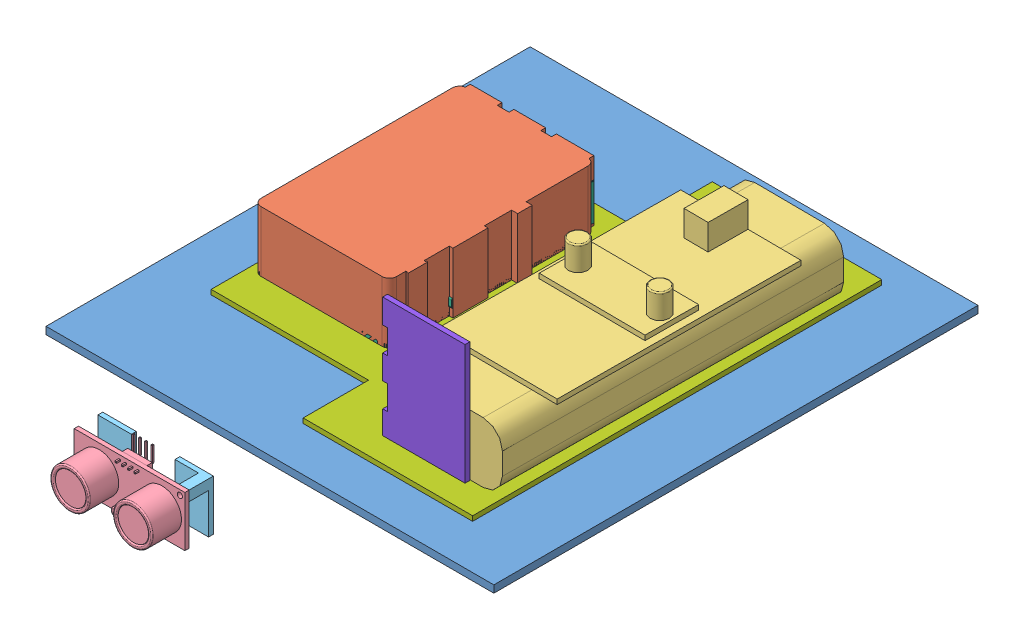
SolidWorks assembly BaugruppeRover, configuration Default. Lengths in mm.
Overall size (185 54.6 278.14).
10 component instances, 9 part files, 6 mates.
Components (placement in the parent):
- Grundplatte Security Rover-1: Grundplatte Security Rover [Default] at (60.9616 101.6265 161.5882) size (185 3 200)
- RaspberrySiluette-1: RaspberrySiluette [Standard] at (50.0622 106.6265 201.3551) x (0.000094 0 -1) z (0 1 0) size (87 58.5 25)
- AkkuSiluette-1: AkkuSiluette [Default] at (104.41 106.6265 160.86) x (0.999975 0 0.007086) z (-0.007086 0 0.999975) size (50 39 140)
- Teil3-1: Teil3 [Standard] at origin
- Baugruppe2-1: Baugruppe2 [Standard] at (48.9446 134.4073 330.5487) x (0 1 0) z (0 0 1) size (25.58 45.72 23.97)
  - hc sr04 ultrasonic sensor2-1: hc sr04 ultrasonic sensor2 [Default] at (-5.0165 -19.9814 -4.7912) size (25.58 45.72 18.36)
  - Teil4-2: Teil4 [Default] at (-5.0155 -19.9814 -12.7912) x (0 -1 0) z (0 0 -1) size (45.72 20.83 10)
- Raspberry Pi 3-1: Raspberry Pi 3 [Default] at (24.4775 106.9565 152.9107) x (0.000094 0 -1) z (0 1 0) size (89.64 57.31 18.92)
- akkuRaspberryBoden-1: akkuRaspberryBoden [Default] at (-8.6363 104.6265 216.2573) x (0 0 -1) z (1 0 0) size (169 2 135)
- wand1-1: wand1 [Default] at (96.1356 130.495 231.1794) size (34.01 53.47 2)
Mates (geometry in assembly coordinates):
- Deckungsgleich6: coincident aligned: plane of RaspberrySiluette-1 through (50.0622 131.6265 201.3551) normal (-0.000094 0 1); plane of Raspberry Pi 3-1 through (-2.9478 106.1965 201.3501) normal (-0.000094 0 1)
- Deckungsgleich7: coincident aligned: plane of RaspberrySiluette-1 through (-5.9378 131.6265 201.3498) normal (-1 0 -0.000094); plane of Raspberry Pi 3-1 through (-5.93 106.1965 119.4156) normal (-1 0 -0.000094)
- Deckungsgleich9: coincident anti-aligned: plane of Grundplatte Security Rover-1 through (60.9616 104.6265 161.5882) normal (0 1 0); plane of akkuRaspberryBoden-1 through (-8.6363 104.6265 216.2573) normal (0 -1 0)
- Deckungsgleich16: coincident anti-aligned: plane of RaspberrySiluette-1 through (50.0622 106.6265 201.3551) normal (0 -1 0); plane of akkuRaspberryBoden-1 through (-8.6363 106.6265 216.2573) normal (0 1 0)
- Deckungsgleich17: coincident aligned: plane of RaspberrySiluette-1 through (50.0622 106.6265 201.3551) normal (0 -1 0); plane of Raspberry Pi 3-1 through (-5.9297 106.6265 116.4256) normal (0 -1 0)
- Deckungsgleich19: coincident anti-aligned: plane of AkkuSiluette-1 through (104.41 106.6265 160.86) normal (0 -1 0); plane of akkuRaspberryBoden-1 through (-8.6363 106.6265 216.2573) normal (0 1 0)
